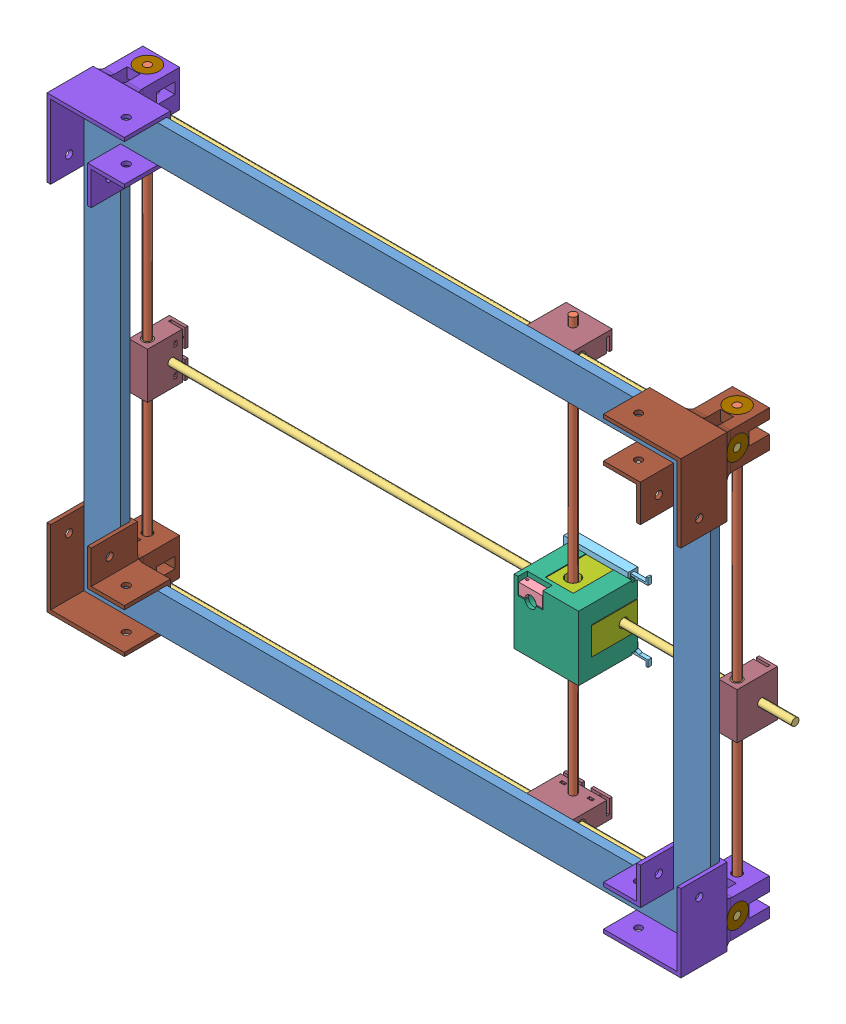
SolidWorks assembly Assemblage_XY, configuration Défaut. Lengths in mm.
Overall size (711.56 489.34 121.29).
48 component instances, 13 part files, 63 mates.
Components (placement in the parent):
- Cadre_XY-1: Cadre_XY [Défaut] at (379.0068 -247.2078 675) size (680 480 10)
- AXE_8X480-1: AXE_8X480 [Défaut] at (359.0068 232.7922 636) x (0.999993 0 -0.00366) z (0 -1 0) size (8 8 480)
- AXE_8X480-2: AXE_8X480 [Défaut] at (-280.9932 -247.2078 636) x (0.987721 0 0.156231) z (0 1 0) size (8 8 480)
- AXE_8X680-1: AXE_8X680 [Défaut] at (379.0068 212.7922 656) x (0 0.013067 0.999915) z (-1 0 0) size (8 8 680)
- AXE_8X680-2: AXE_8X680 [Défaut] at (379.0068 -227.2078 656) x (0 0.106795 0.994281) z (-1 0 0) size (8 8 680)
- AXE_8X480-3: AXE_8X480 [Défaut] at (184.6367 232.7922 639.7) x (0.999527 0 0.030742) z (0 -1 0) size (8 8 480)
- AXE_8X680-3: AXE_8X680 [Défaut] at (-274.1005 -49.7706 619.7) x (0 -0.91678 0.399392) z (1 0 0) size (8 8 680)
- P3DMIPC-Tête_complete-1: P3DMIPC-Tête_complete [Défaut] at (140.444 -36.4005 635.2981) x (0 1 0) z (1 0 0) size (84 69 89)
  - P3DMIPC-Clip_Buse_E3D-1: P3DMIPC-Clip_Buse_E3D [Défaut] at (17.0518 23.4109 40.0035) x (1 0 0) z (0 1 0) size (12 26 10)
  - P3DMIPC-Clip_tête-1: P3DMIPC-Clip_tête [Défaut] at (26.9018 -25.0891 4.5597) x (1 0 0) z (0 -1 0) size (84 89 10.5)
  - P3DMIPC-Porte_Buse_E3DX1-1: P3DMIPC-Porte_Buse_E3DX1 [Défaut] at (22.03 33.4019 79.1927) x (0 0 1) z (0 -1 0) size (70 70 64)
  - P3DMIPC-Chariot-1: P3DMIPC-Chariot [Défaut] at (-48.37 -30.5981 79.1927) size (70 50 70)
- Angle_magique_G-1: Angle_magique_G [Défaut] at (379.0068 -247.2078 675) x (-1 0 0) z (0 0 -1) size (84.67 84.67 100)
- F608ZZ-1: F608ZZ [Défaut] at (372.0068 -227.2078 656) x (0 -0.924225 -0.381849) z (1 0 0) size (25 25 7)
- Angle_magique_G-4: Angle_magique_G [Défaut] at (-300.9932 232.7922 675) x (1 0 0) z (0 0 -1) size (84.67 84.67 100)
- pulley_gt2_3mm_20t-10: pulley_gt2_3mm_20t [Défaut] at (-280.9932 214.0422 636) x (0.106795 0 0.994281) z (0 1 0) size (15 15 10.5)
- pulley_gt2_3mm_20t-11: pulley_gt2_3mm_20t [Défaut] at (-282.2432 212.7922 656) x (0 0.106795 0.994281) z (-1 0 0) size (15 15 10.5)
- pulley_gt2_3mm_20t-12: pulley_gt2_3mm_20t [Défaut] at (-280.9932 -236.4578 636) x (-0.771074 0 0.636745) z (0 1 0) size (15 15 10.5)
- pulley_gt2_3mm_20t-13: pulley_gt2_3mm_20t [Défaut] at (-282.2432 -227.2078 656) x (0 0.106795 0.994281) z (-1 0 0) size (15 15 10.5)
- pulley_gt2_3mm_20t-15: pulley_gt2_3mm_20t [Défaut] at (359.0068 222.0422 636) x (-0.106795 0 0.994281) z (0 -1 0) size (15 15 10.5)
- pulley_gt2_3mm_20t-16: pulley_gt2_3mm_20t [Défaut] at (372.7568 212.7922 656) x (0 0.106795 0.994281) z (-1 0 0) size (15 15 10.5)
- F608ZZ-2: F608ZZ [Défaut] at (-280.9932 225.7922 636) x (-0.546944 0 0.837169) z (0 1 0) size (25 25 7)
- F608ZZ-3: F608ZZ [Défaut] at (-293.9932 212.7922 656) x (0 0 1) z (-1 0 0) size (25 25 7)
- F608ZZ-4: F608ZZ [Défaut] at (-293.9932 -227.2078 656) x (0 0 1) z (-1 0 0) size (25 25 7)
- F608ZZ-5: F608ZZ [Défaut] at (-280.9932 -240.2078 636) x (-0.924225 0 -0.381849) z (0 -1 0) size (25 25 7)
- F608ZZ-6: F608ZZ [Défaut] at (359.0068 -240.2078 636) x (-0.546944 0 0.837169) z (0 -1 0) size (25 25 7)
- F608ZZ-7: F608ZZ [Défaut] at (372.0068 212.7922 656) x (0 0 1) z (1 0 0) size (25 25 7)
- F608ZZ-8: F608ZZ [Défaut] at (359.0068 225.7922 636) x (0 0 1) z (0 1 0) size (25 25 7)
- Angle_magique_D-1: Angle_magique_D [Défaut] at (-300.9932 -247.2078 675) x (0 1 0) z (0 0 -1) size (84.67 84.54 100)
- Angle_magique_D-2: Angle_magique_D [Défaut] at (379.0068 232.7922 675) x (0 -1 0) z (0 0 -1) size (84.67 84.54 100)
- Assemblage_glissière_block_belt_palier-1: Assemblage_glissière_block_belt_palier [Défaut] at (305.1616 -186.4667 607.6689) x (0 -1 0) z (-1 0 0) size (20 43.8 50)
  - ultimaker_cuivre_fritté_douille_8mmx11mmx22 mm-1: ultimaker_cuivre_fritté_douille_8mmx11mmx22 mm [Défaut] at (40.7411 48.3311 95.5249) size (11 11 22)
  - ultimaker_cuivre_fritté_douille_8mmx11mmx22 mm-2: ultimaker_cuivre_fritté_douille_8mmx11mmx22 mm [Défaut] at (40.7411 48.3311 123.5249) size (11 11 22)
  - Glisière_block_belt-2: Glisière_block_belt [Défaut] at (50.7411 14.5311 95.5249) size (20 43.8 50)
- Assemblage_glissière_block_belt_palier-2: Assemblage_glissière_block_belt_palier [Défaut] at (64.1118 172.0511 607.6689) x (0 1 0) z (1 0 0) size (20 43.8 50)
  - ultimaker_cuivre_fritté_douille_8mmx11mmx22 mm-1: ultimaker_cuivre_fritté_douille_8mmx11mmx22 mm [Défaut] at (40.7411 48.3311 95.5249) size (11 11 22)
  - ultimaker_cuivre_fritté_douille_8mmx11mmx22 mm-2: ultimaker_cuivre_fritté_douille_8mmx11mmx22 mm [Défaut] at (40.7411 48.3311 123.5249) size (11 11 22)
  - Glisière_block_belt-2: Glisière_block_belt [Défaut] at (50.7411 14.5311 95.5249) size (20 43.8 50)
- Assemblage_glissière_block_belt_palier-3: Assemblage_glissière_block_belt_palier [Défaut] at (318.2657 70.7544 587.6689) x (1 0 0) z (0 -1 0) size (20 43.8 50)
  - ultimaker_cuivre_fritté_douille_8mmx11mmx22 mm-1: ultimaker_cuivre_fritté_douille_8mmx11mmx22 mm [Défaut] at (40.7411 48.3311 95.5249) size (11 11 22)
  - ultimaker_cuivre_fritté_douille_8mmx11mmx22 mm-2: ultimaker_cuivre_fritté_douille_8mmx11mmx22 mm [Défaut] at (40.7411 48.3311 123.5249) size (11 11 22)
  - Glisière_block_belt-2: Glisière_block_belt [Défaut] at (50.7411 14.5311 95.5249) size (20 43.8 50)
- Assemblage_glissière_block_belt_palier-5: Assemblage_glissière_block_belt_palier [Défaut] at (-240.2522 -170.2955 587.6689) x (-1 0 0) z (0 1 0) size (20 43.8 50)
  - ultimaker_cuivre_fritté_douille_8mmx11mmx22 mm-1: ultimaker_cuivre_fritté_douille_8mmx11mmx22 mm [Défaut] at (40.7411 48.3311 95.5249) size (11 11 22)
  - ultimaker_cuivre_fritté_douille_8mmx11mmx22 mm-2: ultimaker_cuivre_fritté_douille_8mmx11mmx22 mm [Défaut] at (40.7411 48.3311 123.5249) size (11 11 22)
  - Glisière_block_belt-2: Glisière_block_belt [Défaut] at (50.7411 14.5311 95.5249) size (20 43.8 50)
- pulley_gt2_3mm_20t-17: pulley_gt2_3mm_20t [Défaut] at (368.2568 -227.2078 656) x (0 0.106795 0.994281) z (-1 0 0) size (15 15 10.5)
- pulley_gt2_3mm_20t-18: pulley_gt2_3mm_20t [Défaut] at (359.0068 -223.9578 636) x (0.203502 0 0.979074) z (0 -1 0) size (15 15 10.5)
Mates (geometry in assembly coordinates):
- Coaxiale1: concentric anti-aligned: cylinder of AXE_8X680-3 through (405.8995 -49.7706 619.7) axis (-1 0 0) radius 4; cylinder of P3DMIPC-Tête_complete-1/P3DMIPC-Chariot-1 through (215.6367 -49.7706 619.7) axis (1 0 0) radius 5
- Coaxiale2: concentric anti-aligned: cylinder of AXE_8X480-3 through (184.6367 -247.2078 639.7) axis (0 1 0) radius 4; cylinder of P3DMIPC-Tête_complete-1/P3DMIPC-Chariot-1 through (184.6367 -80.7706 639.7) axis (0 -1 0) radius 5
- Coïncidente14: coincident anti-aligned: plane of Cadre_XY-1 through (379.0068 -247.2078 675) normal (0 0 -1); plane of Angle_magique_G-1 through (379.0068 -247.2078 675) normal (0 0 1)
- Coïncidente15: coincident anti-aligned: plane of Cadre_XY-1 through (379.0068 -247.2078 685) normal (1 0 0); plane of Angle_magique_G-1 through (379.0068 -247.2078 721) normal (-1 0 0)
- Coïncidente16: coincident anti-aligned: plane of Cadre_XY-1 through (379.0068 -247.2078 685) normal (0 -1 0); plane of Angle_magique_G-1 through (299.0068 -247.2078 721) normal (0 1 0)
- Coaxiale15: concentric anti-aligned: cylinder of AXE_8X680-2 through (-300.9932 -227.2078 656) axis (1 0 0) radius 4; cylinder of Angle_magique_G-1 through (389.0068 -227.2078 656) axis (-1 0 0) radius 5
- Coïncidente27: coincident anti-aligned: plane of Cadre_XY-1 through (379.0068 -247.2078 675) normal (0 0 -1); plane of Angle_magique_G-4 through (-300.9932 232.7922 675) normal (0 0 1)
- Coïncidente28: coincident anti-aligned: plane of Cadre_XY-1 through (379.0068 232.7922 685) normal (0 1 0); plane of Angle_magique_G-4 through (-220.9932 232.7922 721) normal (0 -1 0)
- Coïncidente29: coincident anti-aligned: plane of Cadre_XY-1 through (-300.9932 -247.2078 685) normal (-1 0 0); plane of Angle_magique_G-4 through (-300.9932 232.7922 721) normal (1 0 0)
- Coaxiale17: concentric anti-aligned: cylinder of AXE_8X680-1 through (-300.9932 212.7922 656) axis (1 0 0) radius 4; cylinder of pulley_gt2_3mm_20t-11 through (-282.2432 212.7922 656) axis (-1 0 0) radius 4
- Coaxiale18: concentric aligned: cylinder of AXE_8X680-1 through (-300.9932 212.7922 656) axis (1 0 0) radius 4; cylinder of Angle_magique_G-4 through (-310.9932 212.7922 656) axis (1 0 0) radius 5
- Coïncidente30: coincident aligned: plane of Cadre_XY-1 through (-300.9932 -247.2078 685) normal (-1 0 0); plane of AXE_8X680-1 through (-300.9932 212.7922 656) normal (-1 0 0)
- Distance2: distance = 7.25 mm anti-aligned: plane of pulley_gt2_3mm_20t-11 through (-283.2432 212.7922 656) normal (1 0 0); plane of Angle_magique_G-4 through (-275.9932 192.7922 621) normal (-1 0 0)
- Coaxiale19: concentric anti-aligned: cylinder of AXE_8X680-1 through (-300.9932 212.7922 656) axis (1 0 0) radius 4; cylinder of pulley_gt2_3mm_20t-16 through (372.7568 212.7922 656) axis (-1 0 0) radius 4
- Coaxiale20: concentric aligned: cylinder of AXE_8X480-1 through (359.0068 -247.2078 636) axis (0 1 0) radius 4; cylinder of Angle_magique_G-1 through (359.0068 -247.2078 636) axis (0 1 0) radius 5
- Coïncidente33: coincident aligned: plane of Cadre_XY-1 through (379.0068 -247.2078 685) normal (0 -1 0); circle of AXE_8X480-1
- Coaxiale22: concentric anti-aligned: cylinder of AXE_8X480-1 through (359.0068 -247.2078 636) axis (0 1 0) radius 4; cylinder of pulley_gt2_3mm_20t-15 through (359.0068 222.0422 636) axis (0 -1 0) radius 4
- Coaxiale23: concentric anti-aligned: cylinder of AXE_8X680-2 through (-300.9932 -227.2078 656) axis (1 0 0) radius 4; cylinder of pulley_gt2_3mm_20t-13 through (-282.2432 -227.2078 656) axis (-1 0 0) radius 4
- Coaxiale24: concentric aligned: cylinder of AXE_8X480-2 through (-280.9932 232.7922 636) axis (0 -1 0) radius 4; cylinder of Angle_magique_G-4 through (-280.9932 232.7923 636) axis (0 -1 0) radius 5
- Coaxiale25: concentric anti-aligned: cylinder of AXE_8X480-2 through (-280.9932 232.7922 636) axis (0 -1 0) radius 4; cylinder of pulley_gt2_3mm_20t-10 through (-280.9932 214.0422 636) axis (0 1 0) radius 4
- Coïncidente34: coincident aligned: plane of Cadre_XY-1 through (379.0068 232.7922 685) normal (0 1 0); plane of AXE_8X480-2 through (-280.9932 232.7922 636) normal (0 1 0)
- Distance4: distance = 7.25 mm anti-aligned: plane of pulley_gt2_3mm_20t-10 through (-280.9932 215.0422 636) normal (0 -1 0); plane of Angle_magique_G-4 through (-275.9932 207.7922 621) normal (0 1 0)
- Coaxiale26: concentric anti-aligned: cylinder of AXE_8X480-2 through (-280.9932 232.7922 636) axis (0 -1 0) radius 4; cylinder of pulley_gt2_3mm_20t-12 through (-280.9932 -236.4578 636) axis (0 1 0) radius 4
- Coïncidente43: coincident aligned: plane of Cadre_XY-1 through (379.0068 -247.2078 685) normal (1 0 0); plane of AXE_8X680-2 through (379.0068 -227.2078 656) normal (1 0 0)
- Coïncidente44: coincident anti-aligned: plane of Cadre_XY-1 through (379.0068 -247.2078 675) normal (0 0 -1); plane of Angle_magique_D-1 through (-300.9932 -247.2078 675) normal (0 0 1)
- Coïncidente45: coincident anti-aligned: plane of Cadre_XY-1 through (379.0068 -247.2078 685) normal (0 -1 0); plane of Angle_magique_D-1 through (-300.9932 -247.2078 721) normal (0 1 0)
- Coïncidente46: coincident anti-aligned: plane of Cadre_XY-1 through (-300.9932 -247.2078 685) normal (-1 0 0); plane of Angle_magique_D-1 through (-300.9932 -167.2078 721) normal (1 0 0)
- Distance9: distance = 7.25 mm anti-aligned: plane of pulley_gt2_3mm_20t-13 through (-283.2432 -227.2078 656) normal (1 0 0); plane of Angle_magique_D-1 through (-275.9932 -222.2078 621) normal (-1 0 0)
- Distance10: distance = 2.75 mm anti-aligned: plane of Angle_magique_D-1 through (-260.9932 -222.2078 621) normal (0 -1 0); plane of pulley_gt2_3mm_20t-12 through (-280.9932 -224.9578 636) normal (0 1 0)
- Coïncidente51: coincident anti-aligned: plane of Cadre_XY-1 through (379.0068 -247.2078 675) normal (0 0 -1); plane of Angle_magique_D-2 through (379.0068 232.7922 675) normal (0 0 1)
- Coïncidente52: coincident anti-aligned: plane of Cadre_XY-1 through (379.0068 232.7922 685) normal (0 1 0); plane of Angle_magique_D-2 through (379.0068 232.7922 721) normal (0 -1 0)
- Coïncidente53: coincident anti-aligned: plane of Cadre_XY-1 through (379.0068 -247.2078 685) normal (1 0 0); plane of Angle_magique_D-2 through (379.0068 152.7922 721) normal (-1 0 0)
- Distance11: distance = 2.75 mm anti-aligned: plane of pulley_gt2_3mm_20t-15 through (359.0068 210.5422 636) normal (0 -1 0); plane of Angle_magique_D-2 through (339.0068 207.7922 621) normal (0 1 0)
- Distance12: distance = 7.25 mm anti-aligned: plane of Angle_magique_D-2 through (354.0068 207.7922 621) normal (1 0 0); plane of pulley_gt2_3mm_20t-16 through (361.2568 212.7922 656) normal (-1 0 0)
- Coaxiale37: concentric aligned: cylinder of AXE_8X680-2 through (-300.9932 -227.2078 656) axis (1 0 0) radius 4; cylinder of Assemblage_glissière_block_belt_palier-1/ultimaker_cuivre_fritté_douille_8mmx11mmx22 mm-1 through (187.6367 -227.2078 656) axis (1 0 0) radius 4
- Coaxiale39: concentric anti-aligned: cylinder of AXE_8X680-1 through (-300.9932 212.7922 656) axis (1 0 0) radius 4; cylinder of Assemblage_glissière_block_belt_palier-2/ultimaker_cuivre_fritté_douille_8mmx11mmx22 mm-1 through (181.6367 212.7922 656) axis (-1 0 0) radius 4
- Coaxiale41: concentric aligned: cylinder of AXE_8X480-1 through (359.0068 -247.2078 636) axis (0 1 0) radius 4; cylinder of Assemblage_glissière_block_belt_palier-3/ultimaker_cuivre_fritté_douille_8mmx11mmx22 mm-2 through (359.0068 -74.7706 636) axis (0 1 0) radius 4
- Coaxiale42: concentric anti-aligned: cylinder of AXE_8X480-3 through (184.6367 -247.2078 639.7) axis (0 1 0) radius 4; cylinder of Assemblage_glissière_block_belt_palier-2/Glisière_block_belt-2 through (184.6367 222.7922 639.7) axis (0 -1 0) radius 4
- Coaxiale43: concentric aligned: cylinder of AXE_8X480-3 through (184.6367 -247.2078 639.7) axis (0 1 0) radius 4; cylinder of Assemblage_glissière_block_belt_palier-1/Glisière_block_belt-2 through (184.6367 -237.2078 639.7) axis (0 1 0) radius 4
- Coïncidente60: coincident aligned: plane of Cadre_XY-1 through (379.0068 232.7922 685) normal (0 1 0); plane of AXE_8X480-3 through (184.6367 232.7922 639.7) normal (0 1 0)
- Coaxiale45: concentric aligned: cylinder of AXE_8X480-2 through (-280.9932 232.7922 636) axis (0 -1 0) radius 4; cylinder of Assemblage_glissière_block_belt_palier-5/ultimaker_cuivre_fritté_douille_8mmx11mmx22 mm-1 through (-280.9932 -52.7706 636) axis (0 -1 0) radius 4
- Coaxiale50: concentric anti-aligned: cylinder of F608ZZ-7 through (377.5068 212.7922 656) axis (-1 0 0) radius 11; cylinder of Angle_magique_D-2 through (372.0068 212.7922 656) axis (1 0 0) radius 11
- Coïncidente63: coincident anti-aligned: plane of F608ZZ-7 through (372.0068 212.7922 656) normal (-1 0 0); plane of Angle_magique_D-2 through (372.0068 212.7922 656) normal (1 0 0)
- Coaxiale51: concentric anti-aligned: cylinder of F608ZZ-8 through (359.0068 231.2922 636) axis (0 -1 0) radius 11; cylinder of Angle_magique_D-2 through (359.0068 225.7922 636) axis (0 1 0) radius 11
- Coïncidente64: coincident anti-aligned: plane of F608ZZ-8 through (359.0068 225.7922 636) normal (0 -1 0); plane of Angle_magique_D-2 through (359.0068 225.7922 636) normal (0 1 0)
- Coïncidente65: coincident anti-aligned: plane of Angle_magique_G-4 through (-280.9932 225.7922 636) normal (0 1 0); plane of F608ZZ-2 through (-280.9932 225.7922 636) normal (0 -1 0)
- Coaxiale53: concentric anti-aligned: cylinder of Angle_magique_G-4 through (-280.9932 225.7922 636) axis (0 1 0) radius 11; cylinder of F608ZZ-2 through (-280.9932 231.2922 636) axis (0 -1 0) radius 11
- Coaxiale54: concentric anti-aligned: cylinder of Angle_magique_G-4 through (-293.9932 212.7922 656) axis (-1 0 0) radius 11; cylinder of F608ZZ-3 through (-299.4932 212.7922 656) axis (1 0 0) radius 11
- Coïncidente66: coincident anti-aligned: plane of Angle_magique_G-4 through (-293.9932 212.7922 656) normal (-1 0 0); plane of F608ZZ-3 through (-293.9932 212.7922 656) normal (1 0 0)
- Coaxiale55: concentric aligned: cylinder of AXE_8X680-3 through (405.8995 -49.7706 619.7) axis (-1 0 0) radius 4; cylinder of Assemblage_glissière_block_belt_palier-3/Glisière_block_belt-2 through (369.0068 -49.7706 619.7) axis (-1 0 0) radius 4
- Coaxiale56: concentric anti-aligned: cylinder of AXE_8X680-3 through (405.8995 -49.7706 619.7) axis (-1 0 0) radius 4; cylinder of Assemblage_glissière_block_belt_palier-5/Glisière_block_belt-2 through (-290.9932 -49.7706 619.7) axis (1 0 0) radius 4
- Coaxiale57: concentric anti-aligned: cylinder of F608ZZ-4 through (-299.4932 -227.2078 656) axis (1 0 0) radius 11; cylinder of Angle_magique_D-1 through (-293.9932 -227.2078 656) axis (-1 0 0) radius 11
- Coïncidente69: coincident anti-aligned: plane of F608ZZ-4 through (-293.9932 -227.2078 656) normal (1 0 0); plane of Angle_magique_D-1 through (-293.9932 -227.2078 656) normal (-1 0 0)
- Coïncidente70: coincident anti-aligned: plane of F608ZZ-5 through (-280.9932 -240.2078 636) normal (0 1 0); plane of Angle_magique_D-1 through (-280.9932 -240.2078 636) normal (0 -1 0)
- Coaxiale58: concentric anti-aligned: cylinder of F608ZZ-5 through (-280.9932 -245.7078 636) axis (0 1 0) radius 11; cylinder of Angle_magique_D-1 through (-280.9932 -240.2078 636) axis (0 -1 0) radius 11
- Coaxiale59: concentric anti-aligned: cylinder of AXE_8X480-1 through (359.0068 -247.2078 636) axis (0 1 0) radius 4; cylinder of pulley_gt2_3mm_20t-18 through (359.0068 -223.9578 636) axis (0 -1 0) radius 4
- Distance14: distance = 2.75 mm anti-aligned: plane of Angle_magique_G-1 through (354.0068 -222.2078 621) normal (0 -1 0); plane of pulley_gt2_3mm_20t-18 through (359.0068 -224.9578 636) normal (0 1 0)
- Coaxiale60: concentric anti-aligned: cylinder of AXE_8X680-2 through (-300.9932 -227.2078 656) axis (1 0 0) radius 4; cylinder of pulley_gt2_3mm_20t-17 through (368.2568 -227.2078 656) axis (-1 0 0) radius 4
- Distance15: distance = 2.75 mm anti-aligned: plane of Angle_magique_G-1 through (354.0068 -207.2078 621) normal (1 0 0); plane of pulley_gt2_3mm_20t-17 through (356.7568 -227.2078 656) normal (-1 0 0)
- Coïncidente73: coincident: plane of Angle_magique_G-1 through (359.0068 -240.2078 636) normal (0 -1 0); plane of F608ZZ-6 through (359.0068 -240.2078 636) normal (0 1 0)
- Coaxiale61: concentric anti-aligned: cylinder of Angle_magique_G-1 through (359.0068 -240.2078 636) axis (0 -1 0) radius 11; cylinder of F608ZZ-6 through (359.0068 -245.7078 636) axis (0 1 0) radius 11
- Coïncidente74: coincident: plane of Angle_magique_G-1 through (372.0068 -227.2078 656) normal (1 0 0); plane of F608ZZ-1 through (372.0068 -121.5479 630.1408) normal (-1 0 0)
- Coaxiale62: concentric anti-aligned: cylinder of Angle_magique_G-1 through (372.0068 -227.2078 656) axis (1 0 0) radius 11; cylinder of F608ZZ-1 through (377.5068 -227.2078 656) axis (-1 0 0) radius 11
